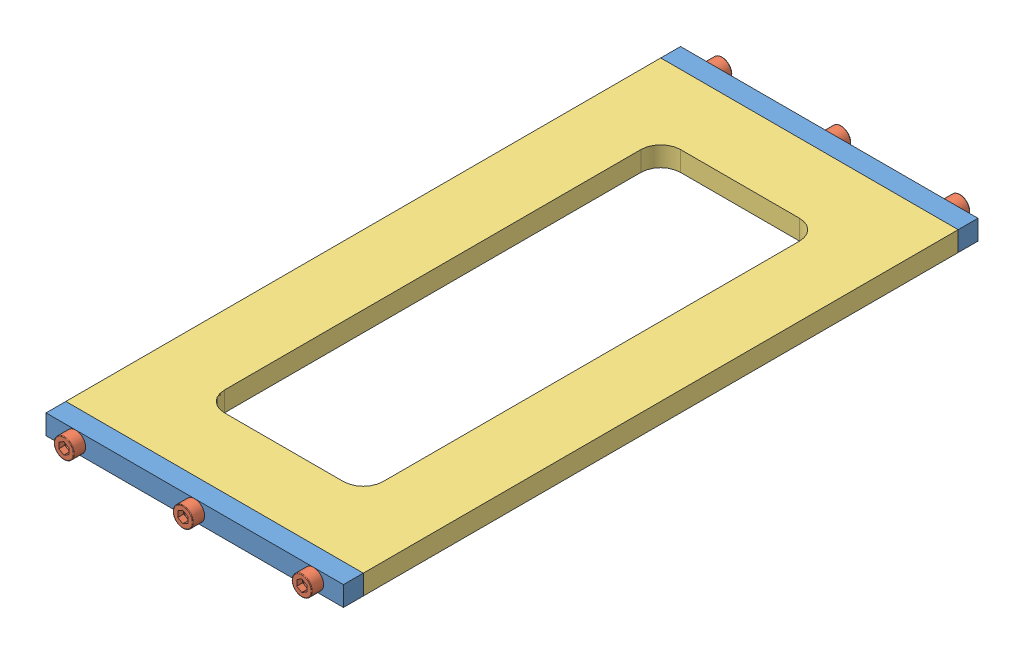
SolidWorks assembly testee - Copy, configuration Default. Lengths in mm.
Overall size (150 10 332).
9 component instances, 3 part files, 26 mates.
Components (placement in the parent):
- pecinha-1: pecinha [Default] at (7.3153 -5.7091 39.1046) x (1 0 0) z (0 1 0) size (150 10 10)
- socket head cap screw_iso-1: socket head cap screw_iso [ISO 4762 M6 x 20 - 20N] at (142.3153 -0.7091 45.1046) x (0 0 -1) z (1 0 0) size (26 10 10)
- socket head cap screw_iso-2: socket head cap screw_iso [ISO 4762 M6 x 20 - 20N] at (82.3153 -0.7091 45.1046) x (0 0 -1) z (1 0 0) size (26 10 10)
- socket head cap screw_iso-3: socket head cap screw_iso [ISO 4762 M6 x 20 - 20N] at (22.3153 -0.7091 45.1046) x (0 0 -1) z (1 0 0) size (26 10 10)
- pecinha-2: pecinha [Default] at (7.3153 4.2909 -280.8954) x (1 0 0) z (0 -1 0) size (150 10 10)
- socket head cap screw_iso-5: socket head cap screw_iso [ISO 4762 M6 x 20 - 20N] at (82.3153 -0.7091 -286.8954) x (0 0 1) z (-1 0 0) size (26 10 10)
- socket head cap screw_iso-6: socket head cap screw_iso [ISO 4762 M6 x 20 - 20N] at (22.3153 -0.7091 -286.8954) x (0 0 1) z (-1 0 0) size (26 10 10)
- socket head cap screw_iso-7: socket head cap screw_iso [ISO 4762 M6 x 20 - 20N] at (142.3153 -0.7091 -286.8954) x (0 0 1) z (-1 0 0) size (26 10 10)
- PLACA B - Copy-1: PLACA B - Copy [Default] at (7.3153 -5.7091 29.1046) size (150 10 300)
Mates (geometry in assembly coordinates):
- Coincident1: coincident anti-aligned: plane of ? through (0 10 0) normal (0 0 1); plane of pecinha-1 through (0 0 0) normal (0 0 -1)
- Coincident2: coincident aligned: plane of ? through (0 10 0) normal (0 1 0); plane of pecinha-1 through (0 10 0) normal (0 1 0)
- Coincident3: coincident aligned: plane of ? through (150 10 0) normal (1 0 0); plane of pecinha-1 through (150 0 0) normal (1 0 0)
- Concentric1: concentric anti-aligned: cylinder of pecinha-1 through (142.3153 -0.7091 39.1046) axis (0 0 -1) radius 3.5; cylinder of socket head cap screw_iso-1 through (142.3153 -0.7091 76.8546) axis (0 0 1) radius 5
- Coincident4: coincident anti-aligned: plane of pecinha-1 through (7.3153 -5.7091 39.1046) normal (0 0 1); plane of socket head cap screw_iso-1 through (142.3153 4.2909 39.1046) normal (0 0 -1)
- Concentric2: concentric anti-aligned: cylinder of pecinha-1 through (82.3153 -0.7091 39.1046) axis (0 0 -1) radius 3.5; cylinder of socket head cap screw_iso-2 through (82.3153 -0.7091 76.8546) axis (0 0 1) radius 5
- Coincident5: coincident anti-aligned: plane of pecinha-1 through (7.3153 -5.7091 39.1046) normal (0 0 1); plane of socket head cap screw_iso-2 through (82.3153 4.2909 39.1046) normal (0 0 -1)
- Concentric3: concentric anti-aligned: cylinder of pecinha-1 through (22.3153 -0.7091 39.1046) axis (0 0 -1) radius 3.5; cylinder of socket head cap screw_iso-3 through (22.3153 -0.7091 76.8546) axis (0 0 1) radius 5
- Coincident6: coincident anti-aligned: plane of pecinha-1 through (7.3153 -5.7091 39.1046) normal (0 0 1); plane of socket head cap screw_iso-3 through (22.3153 4.2909 39.1046) normal (0 0 -1)
- Coincident7: coincident aligned: plane of ? through (0 10 0) normal (0 1 0); plane of pecinha-2 through (0 10 -300) normal (0 1 0)
- Coincident8: coincident aligned: plane of ? through (150 10 0) normal (1 0 0); plane of pecinha-2 through (150 10 -300) normal (1 0 0)
- Coincident9: coincident anti-aligned: plane of ? through (0 10 -300) normal (0 0 -1); plane of pecinha-2 through (0 10 -300) normal (0 0 1)
- Concentric4: concentric aligned: cylinder of ? through (135 5 -300) axis (0 0 -1) radius 2.5; cylinder of ? through (135 5 -337.75) axis (0 0 -1) radius 5
- Coincident10: coincident anti-aligned: plane of ? through (0 10 -300) normal (0 0 -1); plane of ? through (135 10 -300) normal (0 0 1)
- Concentric5: concentric anti-aligned: cylinder of pecinha-2 through (82.3153 -0.7091 -280.8954) axis (0 0 1) radius 3.5; cylinder of socket head cap screw_iso-5 through (82.3153 -0.7091 -318.6454) axis (0 0 -1) radius 5
- Coincident11: coincident anti-aligned: plane of pecinha-2 through (7.3153 4.2909 -280.8954) normal (0 0 -1); plane of socket head cap screw_iso-5 through (82.3153 4.2909 -280.8954) normal (0 0 1)
- Concentric6: concentric anti-aligned: cylinder of pecinha-2 through (22.3153 -0.7091 -280.8954) axis (0 0 1) radius 3.5; cylinder of socket head cap screw_iso-6 through (22.3153 -0.7091 -318.6454) axis (0 0 -1) radius 5
- Coincident12: coincident anti-aligned: plane of pecinha-2 through (7.3153 4.2909 -280.8954) normal (0 0 -1); plane of socket head cap screw_iso-6 through (22.3153 4.2909 -280.8954) normal (0 0 1)
- Concentric7: concentric anti-aligned: cylinder of pecinha-2 through (142.3153 -0.7091 -280.8954) axis (0 0 1) radius 3.5; cylinder of socket head cap screw_iso-7 through (142.3153 -0.7091 -318.6454) axis (0 0 -1) radius 5
- Coincident13: coincident anti-aligned: plane of pecinha-2 through (7.3153 4.2909 -280.8954) normal (0 0 -1); plane of socket head cap screw_iso-7 through (142.3153 4.2909 -280.8954) normal (0 0 1)
- Coincident14: coincident aligned: plane of pecinha-1 through (7.3153 4.2909 29.1046) normal (0 1 0); plane of PLACA B - Copy-1 through (7.3153 4.2909 29.1046) normal (0 1 0)
- Coincident15: coincident aligned: plane of pecinha-2 through (157.3153 4.2909 -270.8954) normal (1 0 0); plane of PLACA B - Copy-1 through (157.3153 4.2909 29.1046) normal (1 0 0)
- Coincident16: coincident anti-aligned: plane of pecinha-2 through (7.3153 4.2909 -270.8954) normal (0 0 1); plane of PLACA B - Copy-1 through (7.3153 4.2909 -270.8954) normal (0 0 -1)
- Coincident20: coincident anti-aligned: plane of pecinha-1 through (7.3153 -5.7091 29.1046) normal (0 0 -1); plane of PLACA B - Copy-1 through (7.3153 4.2909 29.1046) normal (0 0 1)
- Coincident21: coincident aligned: plane of pecinha-1 through (157.3153 -5.7091 29.1046) normal (1 0 0); plane of PLACA B - Copy-1 through (157.3153 4.2909 29.1046) normal (1 0 0)
- Coincident22: coincident aligned: plane of pecinha-2 through (7.3153 -5.7091 -270.8954) normal (0 -1 0); plane of PLACA B - Copy-1 through (7.3153 -5.7091 29.1046) normal (0 -1 0)
